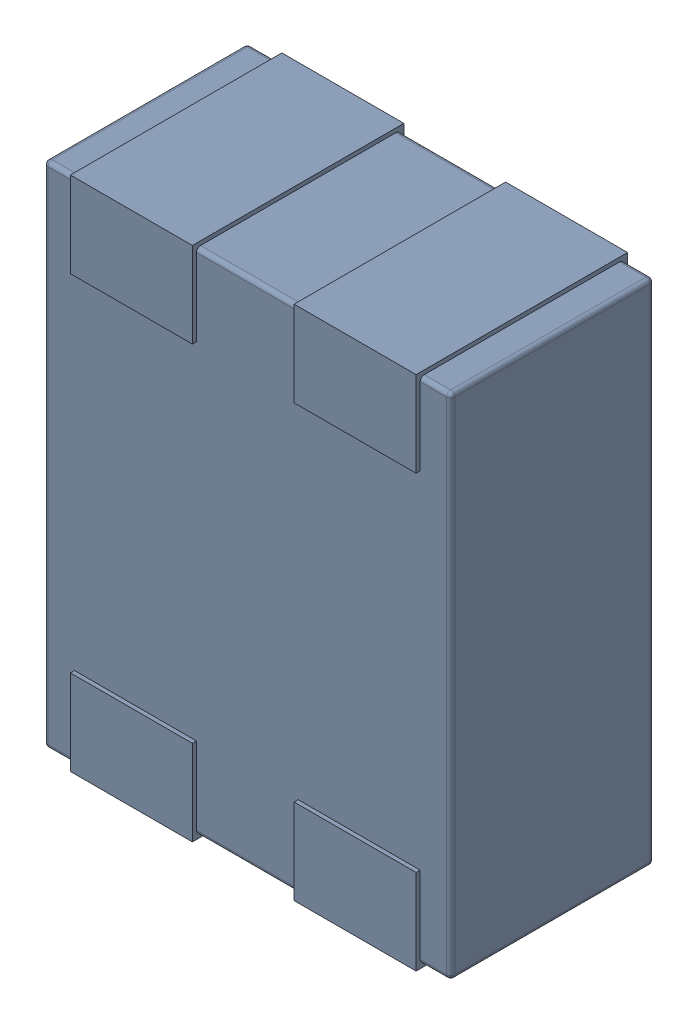
SolidWorks assembly L20, configuration Défaut. Lengths in mm.
Overall size (1 1.27 0.52).
4 component instances, 1 part files, 0 mates.
Components (placement in the parent):
- MCZ1210DH900L2TA0G-1: MCZ1210DH900L2TA0G [Défaut] at (59.1723 -40.4565 -1.6) x (-1 0 0) z (0 0 1) size (1 1.27 0.52)
  - 3D_PCB1_2021-12-30 (1).step-1: 3D_PCB1_2021-12-30 (1).step [Défaut] at origin size (1 1.27 0.52)
    - a3ec64f90eb5404ebd79eca0046a794a.step-1: a3ec64f90eb5404ebd79eca0046a794a.step [Défaut] at (5.0419 -6.8961 1.6) size (1 1.27 0.52)
      - SOLID.step_650-1: SOLID.step_650 [Défaut] at origin size (1 1.27 0.52)
